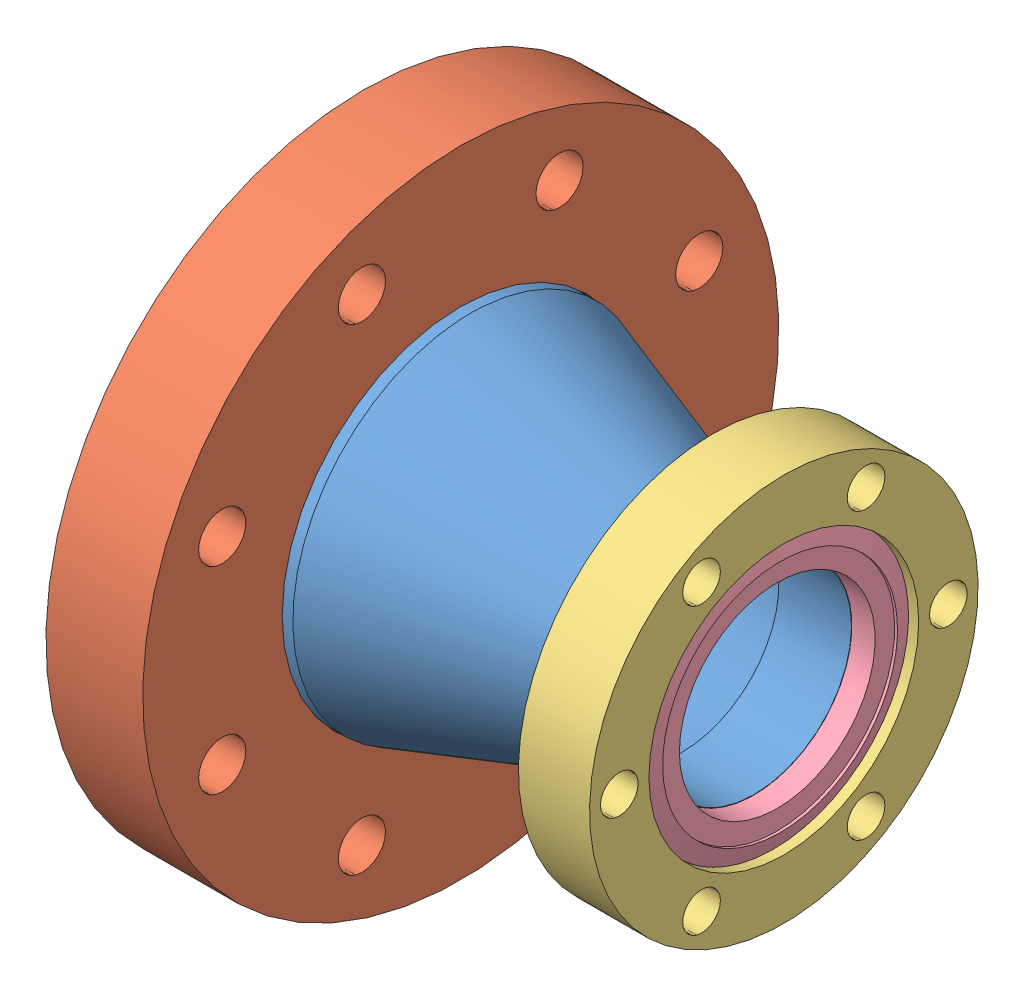
SolidWorks assembly 402032, configuration Default. Lengths in mm.
Overall size (74.93 113.54 113.54).
5 component instances, 4 part files, 0 mates.
Components (placement in the parent):
- 402032-001-1: 402032-001 [Default] at origin size (60.1 63.5 63.5)
- 110021 (4.5 X 2.5 NR)-1: 110021 (4.5 X 2.5 NR) [Default] at (-9.525 0 0) size (17.27 113.54 113.54)
- 100014 (2.75 X 1.5 R)-1: 100014 (2.75 X 1.5 R) [Default] at (65.405 0 0) x (-1 0 0) z (0 0 -1) size (12.7 69.34 69.34)
  - 100014 (2.75 X 1.5 REC)_1-1: 100014 (2.75 X 1.5 REC)_1 [Default] at origin size (12.7 69.34 69.34)
  - 100014 (2.75 X 1.5 INS)-1: 100014 (2.75 X 1.5 INS) [Default] at (1.17 0 0) x (1 0 0) z (0 0.994423 -0.105464) size (6.96 48.1 48.1)
